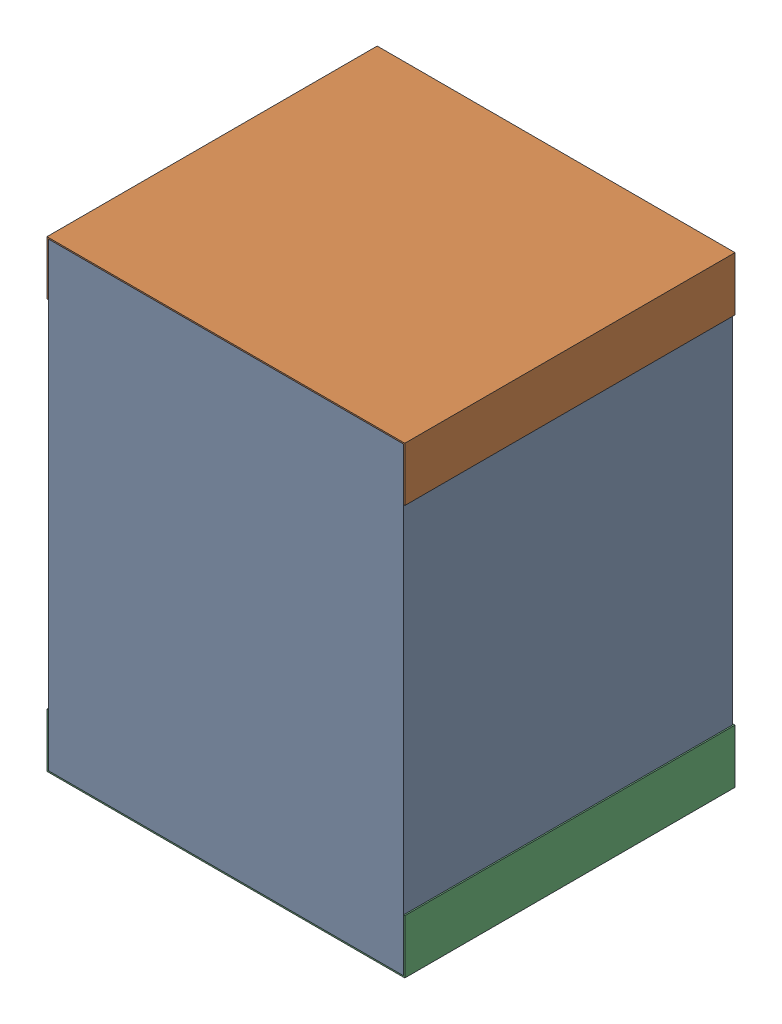
SolidWorks assembly C33, configuration Default. Lengths in mm.
Overall size (2.72 3.52 2.51).
6 component instances, 2 part files, 0 mates.
Components (placement in the parent):
- 870945120-1: 870945120 [Default] at (19.431 43.688 -4.1006) size (2.7 3.5 2.5)
  - Extruded_6-1: Extruded_6 [Default] at origin size (2.7 3.5 2.5)
- 870945280-1: 870945280 [Default] at (19.431 45.243 -4.1106) size (2.72 0.41 2.51)
  - Extruded_7-1: Extruded_7 [Default] at origin size (2.72 0.41 2.51)
- 870945280-2: 870945280 [Default] at (19.431 42.133 -4.1106) size (2.72 0.41 2.51)
  - Extruded_7-1: Extruded_7 [Default] at origin size (2.72 0.41 2.51)
